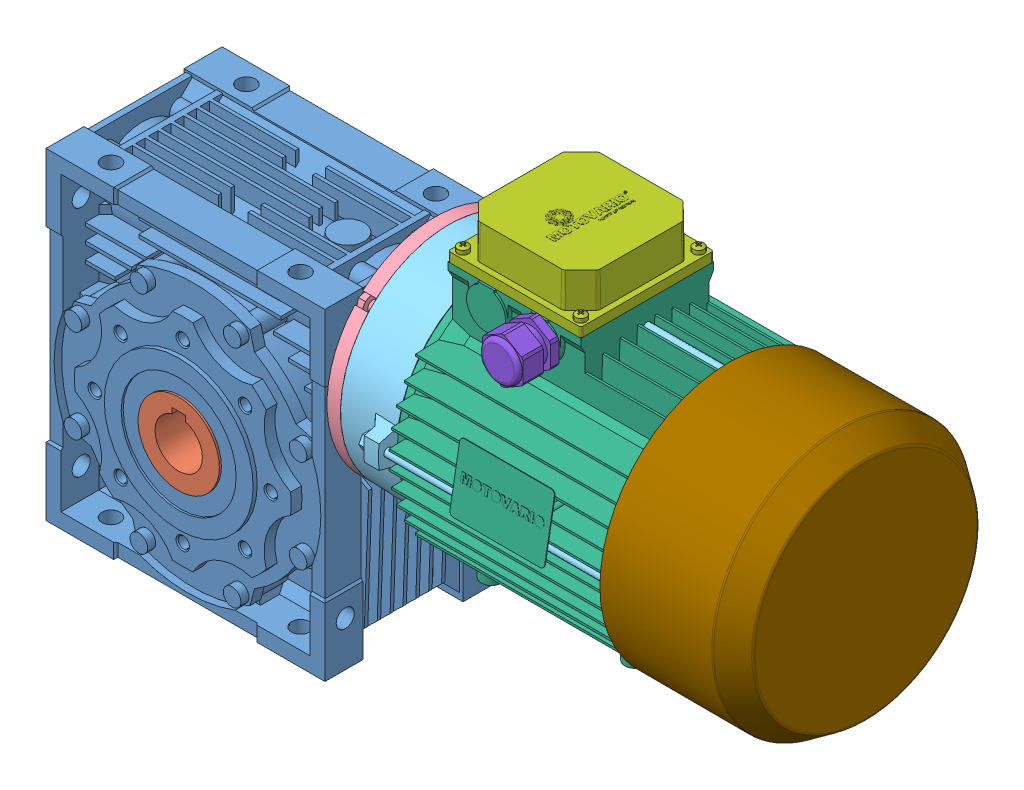
SolidWorks assembly NMRV0907_513013511100300T1001_2_14, configuration Domyślna. Lengths in mm.
Overall size (540.5 330.6 192.14).
12 component instances, 11 part files, 0 mates.
Components (placement in the parent):
- NMRV0907_513013511100300T1001_2_14.stp-1: NMRV0907_513013511100300T1001_2_14.stp [Domyślna] at origin size (540.5 330.6 192.14)
  - _Gear unit 90.stp-1: _Gear unit 90.stp [Domyślna] x (0 0 -1) z (0 1 0) size (140 212 238)
  - _090-35 (140).stp-1: _090-35 (140).stp [Domyślna] x (0 0 1) z (-1 0 0) size (140 60 60)
  - _VB 090-28 (28).stp-1: _VB 090-28 (28).stp [Domyślna] at (0 90 0) size (125 40 40)
  - _90-100-112 B14.stp-1: _90-100-112 B14.stp [Domyślna] at (98 90 0) size (51.5 160 160)
  - _FLANGIA_T100B14-.stp-1: _FLANGIA_T100B14-.stp [Domyślna] at (172.5 90 0) x (-1 0 0) z (0 0 -1) size (231.5 190 190)
  - _CARCASSA_T100IC411B1428X60NONO--.stp-1: _CARCASSA_T100IC411B1428X60NONO--.stp [Domyślna] at (353.5 90 0) x (-1 0 0) z (0 0 -1) size (184 197.51 189.2)
  - _COPRIMORSETTIERA_T100A002.stp-1: _COPRIMORSETTIERA_T100A002.stp [Domyślna] at (227 195 0) size (98 32.6 98)
  - _PRESSACAVO_3.stp-1: _PRESSACAVO_3.stp [Domyślna] at (246.5 180.1 39.75) x (0 0 1) z (1 0 0) size (40.5 33.4 30)
  - _COPRIVENTOLA_T_100_IC411_NO_-_-_-_-_STD.stp-1: _COPRIVENTOLA_T_100_IC411_NO_-_-_-_-_STD.stp [Domyślna] at (336.5 90 0) size (101 190.9 190.9)
  - _TIPPO_25.stp-1: _TIPPO_25.stp [Domyślna] at (246.5 180.1 -50.75) x (0 0 -1) z (1 0 0) size (16.99 30 30)
  - _ALBERO_T10028X60NO.stp-1: _ALBERO_T10028X60NO.stp [Domyślna] at (129.5 90 0) size (90 32 30)
